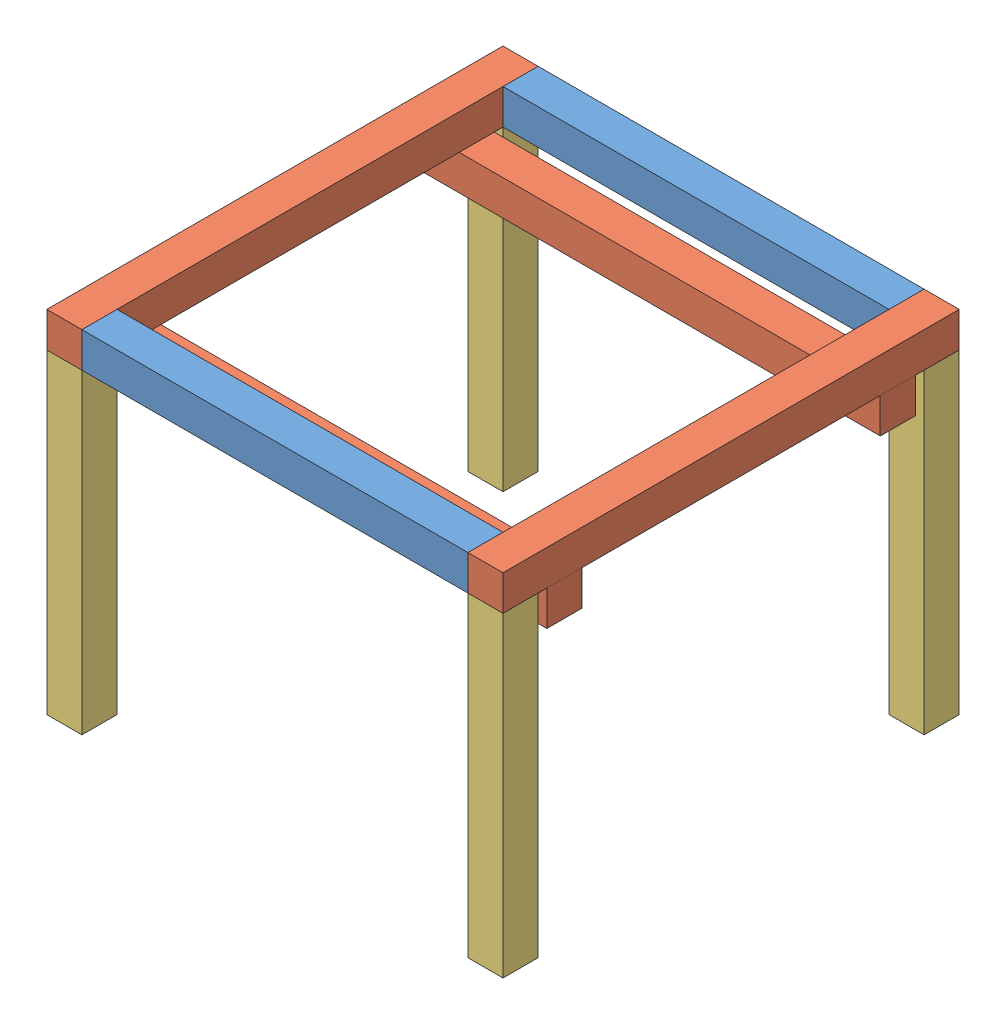
SolidWorks assembly BowlHolder, configuration Default. Lengths in mm.
Overall size (330.2 254 330.2).
10 component instances, 3 part files, 27 mates.
Components (placement in the parent):
- 9.5in-1: 9.5in [Default] at (108.737 108.4161 187.2628) size (279.4 25.4 25.4)
- 11.5in-1: 11.5in [Default] at (261.137 108.4161 339.6628) x (0 0 1) z (-1 0 0) size (330.2 25.4 25.4)
- 9.5in-2: 9.5in [Default] at (108.737 108.4161 492.0628) size (279.4 25.4 25.4)
- 11.5in-2: 11.5in [Default] at (-43.663 108.4161 339.6628) x (0 0 -1) z (1 0 0) size (330.2 25.4 25.4)
- 11.5in-3: 11.5in [Default] at (108.737 108.4161 219.0128) x (-1 0 0) z (0 0 1) size (330.2 25.4 25.4)
- 11.5in-4: 11.5in [Default] at (108.737 83.0161 460.3128) size (330.2 25.4 25.4)
- 9in-1: 9in [Default] at (248.437 -5.8839 187.2628) x (0 -1 0) z (0 0 1) size (228.6 25.4 25.4)
- 9in-2: 9in [Default] at (273.837 -5.8839 492.0628) x (0 1 0) z (0 0 1) size (228.6 25.4 25.4)
- 9in-3: 9in [Default] at (-30.963 -5.8839 492.0628) x (0 1 0) z (0 0 1) size (228.6 25.4 25.4)
- 9in-4: 9in [Default] at (-56.363 -5.8839 187.2628) x (0 -1 0) z (0 0 1) size (228.6 25.4 25.4)
Mates (geometry in assembly coordinates):
- Coincident1: coincident aligned: plane of 9.5in-2 through (108.737 133.8161 492.0628) normal (0 1 0); plane of 11.5in-2 through (-43.663 133.8161 339.6628) normal (0 1 0)
- Coincident2: coincident aligned: plane of 9.5in-1 through (108.737 133.8161 187.2628) normal (0 1 0); plane of 11.5in-2 through (-43.663 133.8161 339.6628) normal (0 1 0)
- Coincident3: coincident aligned: plane of 9.5in-1 through (108.737 133.8161 187.2628) normal (0 1 0); plane of 11.5in-1 through (261.137 133.8161 339.6628) normal (0 1 0)
- Coincident4: coincident anti-aligned: plane of 9.5in-2 through (-30.963 133.8161 504.7628) normal (-1 0 0); plane of 11.5in-2 through (-30.963 133.8161 504.7628) normal (1 0 0)
- Coincident5: coincident: plane of 9.5in-2 through (-30.963 133.8161 504.7628) normal (0 0 1); line of 11.5in-2 through (-56.363 133.8161 504.7628) axis (1 0 0)
- Coincident6: coincident anti-aligned: plane of 9.5in-1 through (-30.963 133.8161 199.9628) normal (-1 0 0); plane of 11.5in-2 through (-30.963 133.8161 504.7628) normal (1 0 0)
- Coincident7: coincident aligned: plane of 9.5in-1 through (-30.963 133.8161 174.5628) normal (0 0 -1); plane of 11.5in-2 through (-30.963 133.8161 174.5628) normal (0 0 -1)
- Coincident8: coincident aligned: plane of 9.5in-1 through (-30.963 133.8161 174.5628) normal (0 0 -1); plane of 11.5in-1 through (248.437 133.8161 174.5628) normal (0 0 -1)
- Coincident9: coincident anti-aligned: plane of 11.5in-1 through (248.437 133.8161 174.5628) normal (-1 0 0); plane of 9.5in-2 through (248.437 133.8161 504.7628) normal (1 0 0)
- Coincident10: coincident anti-aligned: plane of 11.5in-2 through (-43.663 108.4161 339.6628) normal (0 -1 0); plane of 11.5in-4 through (108.737 108.4161 460.3128) normal (0 1 0)
- Coincident11: coincident anti-aligned: plane of 11.5in-2 through (-43.663 108.4161 339.6628) normal (0 -1 0); plane of 11.5in-3 through (108.737 108.4161 219.0128) normal (0 1 0)
- Coincident12: coincident aligned: plane of 11.5in-2 through (-56.363 133.8161 504.7628) normal (-1 0 0); plane of 11.5in-3 through (-56.363 83.0161 231.7128) normal (-1 0 0)
- Coincident13: coincident aligned: plane of 11.5in-2 through (-56.363 133.8161 504.7628) normal (-1 0 0); plane of 11.5in-4 through (-56.363 108.4161 473.0128) normal (-1 0 0)
- Distance1: distance = 31.75 mm aligned: plane of 11.5in-3 through (273.837 83.0161 206.3128) normal (0 0 -1); plane of 9.5in-1 through (-30.963 133.8161 174.5628) normal (0 0 -1)
- Distance2: distance = 31.75 mm aligned: plane of 11.5in-4 through (-56.363 108.4161 473.0128) normal (0 0 1); plane of 9.5in-2 through (-30.963 133.8161 504.7628) normal (0 0 1)
- Coincident16: coincident anti-aligned: plane of 11.5in-2 through (-43.663 108.4161 339.6628) normal (0 -1 0); plane of 9in-4 through (-30.963 108.4161 199.9628) normal (0 1 0)
- Coincident17: coincident aligned: plane of 11.5in-2 through (-56.363 133.8161 504.7628) normal (-1 0 0); plane of 9in-4 through (-56.363 -5.8839 187.2628) normal (-1 0 0)
- Coincident18: coincident aligned: plane of 9.5in-1 through (-30.963 133.8161 174.5628) normal (0 0 -1); plane of 9in-4 through (-30.963 108.4161 174.5628) normal (0 0 -1)
- Coincident19: coincident anti-aligned: plane of 11.5in-1 through (261.137 108.4161 339.6628) normal (0 -1 0); plane of 9in-1 through (273.837 108.4161 199.9628) normal (0 1 0)
- Coincident20: coincident aligned: plane of 9.5in-1 through (-30.963 133.8161 174.5628) normal (0 0 -1); plane of 9in-1 through (273.837 108.4161 174.5628) normal (0 0 -1)
- Coincident21: coincident anti-aligned: line of 11.5in-1 through (273.837 133.8161 174.5628) axis (0 -1 0); line of 9in-1 through (273.837 -120.1839 174.5628) axis (0 1 0)
- Coincident22: coincident anti-aligned: plane of 11.5in-1 through (261.137 108.4161 339.6628) normal (0 -1 0); plane of 9in-2 through (248.437 108.4161 504.7628) normal (0 1 0)
- Coincident23: coincident aligned: plane of 11.5in-1 through (273.837 133.8161 174.5628) normal (1 0 0); plane of 9in-2 through (273.837 -5.8839 492.0628) normal (1 0 0)
- Coincident24: coincident aligned: plane of 11.5in-1 through (248.437 133.8161 504.7628) normal (0 0 1); plane of 9in-2 through (248.437 -120.1839 504.7628) normal (0 0 1)
- Coincident25: coincident anti-aligned: plane of 11.5in-2 through (-43.663 108.4161 339.6628) normal (0 -1 0); plane of 9in-3 through (-56.363 108.4161 504.7628) normal (0 1 0)
- Coincident26: coincident aligned: plane of 9.5in-2 through (-30.963 133.8161 504.7628) normal (0 0 1); plane of 9in-3 through (-56.363 -120.1839 504.7628) normal (0 0 1)
- Coincident27: coincident: line of 11.5in-2 through (-56.363 133.8161 174.5628) axis (0 0 1); plane of 9in-3 through (-56.363 -5.8839 492.0628) normal (-1 0 0)
